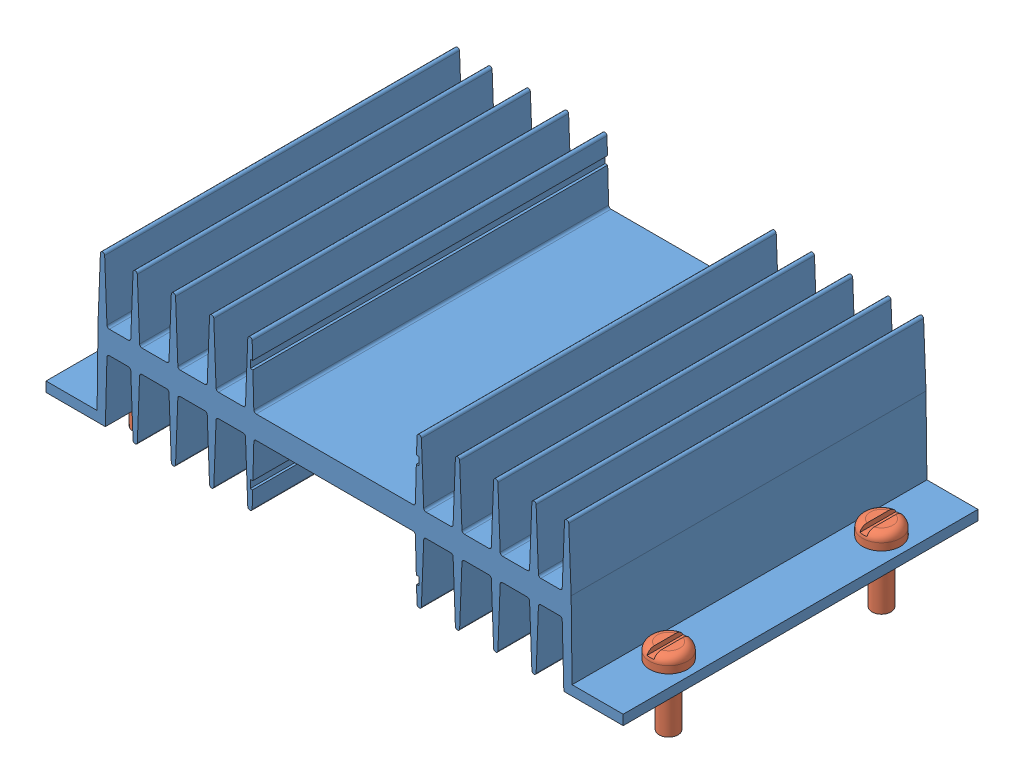
SolidWorks assembly Heatsink SK39 - 75mm, configuration SK39-75. Lengths in mm.
Overall size (122 42.61 75).
5 component instances, 2 part files, 8 mates.
Components (placement in the parent):
- Heatsink SK39-1: Heatsink SK39 [SK39-075] at origin size (122 31.73 75)
- pan slot head_am-1: pan slot head_am [B18.6.7M - M4 x 0.7 x 13 Slotted PHMS --13N] at (55.6 -10.65 22.5) x (0 -1 0) z (0 0 -1) size (16.21 8 8)
- pan slot head_am-2: pan slot head_am [B18.6.7M - M4 x 0.7 x 13 Slotted PHMS --13N] at (55.6 -10.65 -22.5) x (0 -1 0) z (0 0 -1) size (16.21 8 8)
- pan slot head_am-3: pan slot head_am [B18.6.7M - M4 x 0.7 x 13 Slotted PHMS --13N] at (-55.6 -10.65 -22.5) x (0 -1 0) z (0 0 1) size (16.21 8 8)
- pan slot head_am-4: pan slot head_am [B18.6.7M - M4 x 0.7 x 13 Slotted PHMS --13N] at (-55.6 -10.65 22.5) x (0 -1 0) z (0 0 1) size (16.21 8 8)
Mates (geometry in assembly coordinates):
- Concentric1: concentric: cylinder of Heatsink SK39-1 through (55.6 -15.8647 22.5) axis (0 1 0) radius 2.1; cylinder of pan slot head_am-1 through (55.6 14.75 22.5) axis (0 1 0) radius 4
- Coincident5: coincident: plane of Heatsink SK39-1 through (61 -13.75 37.5) normal (0 1 0); plane of pan slot head_am-1 through (53.6 -13.75 22.5) normal (0 -1 0)
- Concentric2: concentric: cylinder of Heatsink SK39-1 through (55.6 -15.8647 -22.5) axis (0 1 0) radius 2.1; cylinder of pan slot head_am-2 through (55.6 14.75 -22.5) axis (0 1 0) radius 4
- Coincident6: coincident: plane of Heatsink SK39-1 through (61 -13.75 37.5) normal (0 1 0); plane of pan slot head_am-2 through (53.6 -13.75 -22.5) normal (0 -1 0)
- Concentric3: concentric: cylinder of Heatsink SK39-1 through (-55.6 -15.8647 -22.5) axis (0 1 0) radius 2.1; cylinder of pan slot head_am-3 through (-55.6 -42.25 -22.5) axis (0 -1 0) radius 4
- Coincident3: coincident anti-aligned: plane of Heatsink SK39-1 through (-61 -13.75 37.5) normal (0 1 0); plane of pan slot head_am-3 through (-53.6 -13.75 -22.5) normal (0 -1 0)
- Concentric4: concentric aligned: cylinder of Heatsink SK39-1 through (-55.6 -15.8647 22.5) axis (0 1 0) radius 2.1; cylinder of pan slot head_am-4 through (-55.6 14.75 22.5) axis (0 1 0) radius 4
- Coincident4: coincident anti-aligned: plane of Heatsink SK39-1 through (-61 -13.75 37.5) normal (0 1 0); plane of pan slot head_am-4
